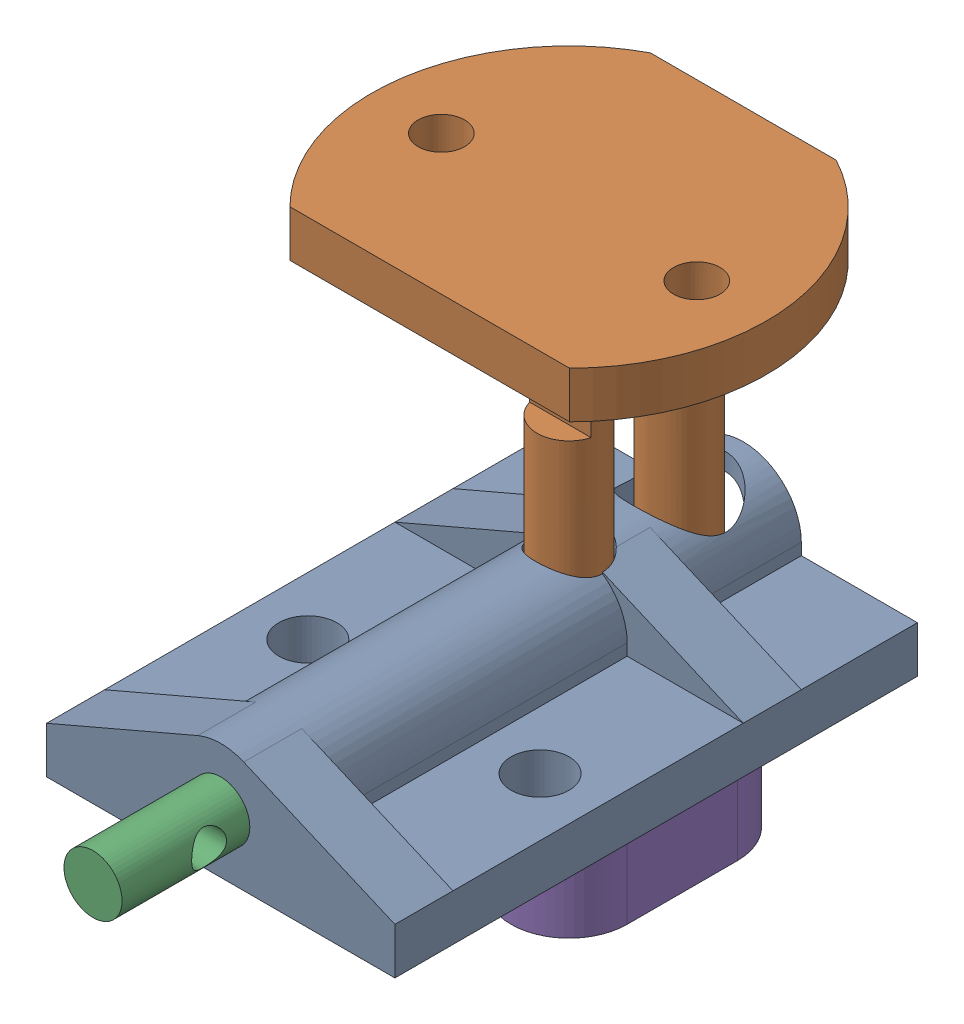
SolidWorks assembly Quick Release Subassembly, configuration Default. Lengths in mm.
Overall size (34 51 56).
5 component instances, 5 part files, 10 mates.
Components (placement in the parent):
- Quick Release Housing-1: Quick Release Housing [Default] at origin size (30 10 45)
- Quick Release Rod-1: Quick Release Rod [Default] at (0 30 -12.5) x (0 0 1) z (1 0 0) size (27 50 34)
- Quick Release Spring Loaded Rod-1: Quick Release Spring Loaded Rod [Default] at (0 0 -6.5) size (7 7 40)
- Spring-1: Spring [Default] at (0 0 -15) size (7 7 30)
- Quick Release Peg-1: Quick Release Peg [Default] at (0 -21 -12.5) x (0 0 1) z (0 1 0) size (19.5 10 10)
Mates (geometry in assembly coordinates):
- Concentric1: concentric anti-aligned: cylinder of Quick Release Housing-1 through (0 5 -12.5) axis (0 -1 0) radius 2.875; cylinder of Quick Release Rod-1 through (0 -20 -12.5) axis (0 1 0) radius 2.75
- Parallel1: parallel aligned: plane of Quick Release Housing-1 through (0 0 17.5) normal (0 0 1); plane of Quick Release Rod-1 through (17 14.5 -11.75) normal (0 0 1)
- Concentric2: concentric anti-aligned: cylinder of Quick Release Housing-1 through (0 0 17.5) axis (0 0 -1) radius 2.5; cylinder of Quick Release Spring Loaded Rod-1 through (0 0 -11.5) axis (0 0 1) radius 2.5
- LimitDistance1: limit distance = 20 mm anti-aligned: plane of Quick Release Spring Loaded Rod-1 through (0 0 -5) normal (0 0 1); plane of Quick Release Housing-1 through (0 0 15) normal (0 0 -1)
- Parallel2: parallel anti-aligned: line of Quick Release Rod-1 through (2.6458 14.5 -11.75) axis (-1 0 0); line of Quick Release Spring Loaded Rod-1 through (-2.5 0 -11.5) axis (1 0 0)
- Concentric3: concentric aligned: cylinder of Quick Release Housing-1 through (0 0 15) axis (0 0 -1) radius 3.5; cylinder of Spring-1 through (0 0 15) axis (0 0 -1) radius 3.5
- Coincident4: coincident anti-aligned: plane of Quick Release Housing-1 through (0 0 15) normal (0 0 -1); plane of Spring-1 through (0 0 15) normal (0 0 1)
- LimitDistance2: limit distance = 35 mm anti-aligned: plane of Quick Release Housing-1 through (-5 -5 -27.5) normal (0 -1 0); plane of Quick Release Rod-1 through (0 30 -12.5) normal (0 1 0)
- Concentric4: concentric anti-aligned: cylinder of Quick Release Rod-1 through (0 -16 -0.5) axis (0 0 -1) radius 1.625; cylinder of Quick Release Peg-1 through (0 -16 -27) axis (0 0 1) radius 1.625
- Concentric5: concentric anti-aligned: cylinder of Quick Release Rod-1 through (0 -20 -12.5) axis (0 1 0) radius 2.75; cylinder of Quick Release Peg-1 through (0 -11 -12.5) axis (0 -1 0) radius 2.875
